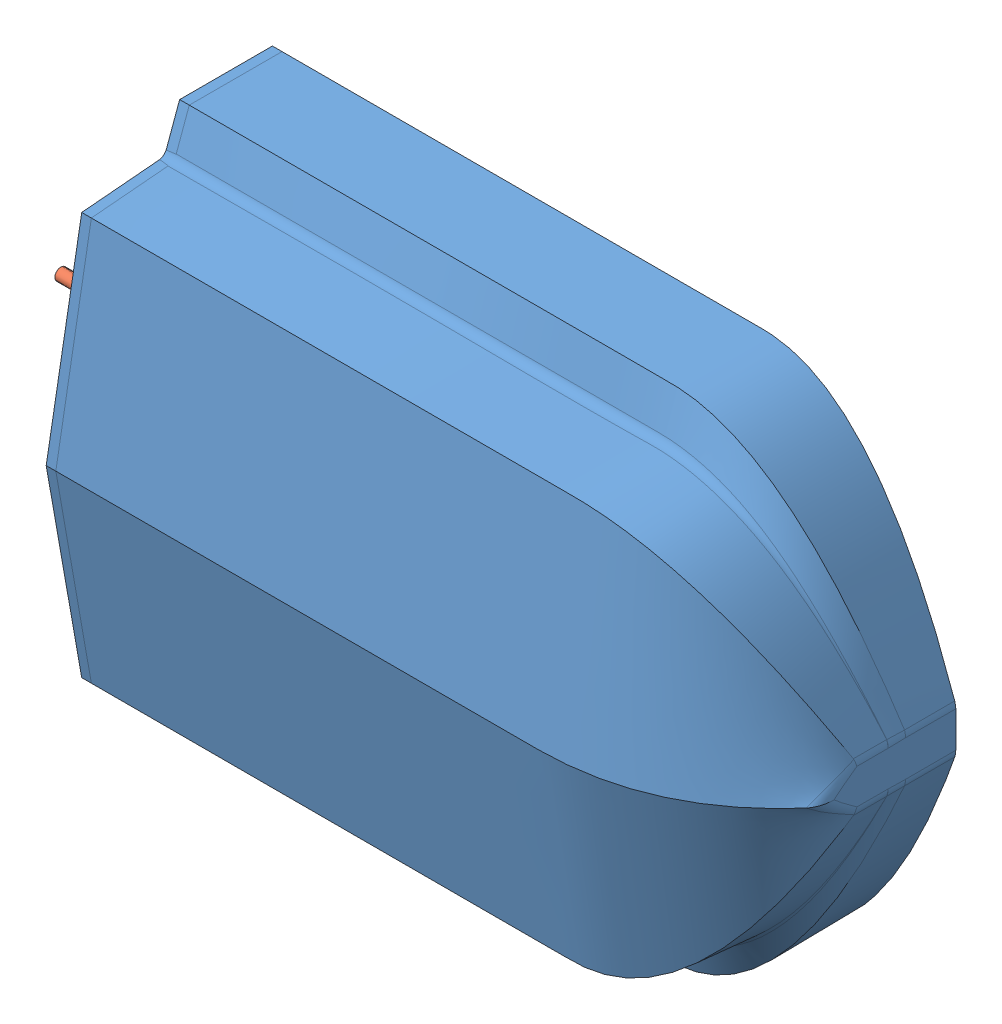
SolidWorks assembly Boat_Assem, configuration Default. Lengths in mm.
Overall size (99.88 66.55 32.05).
3 component instances, 2 part files, 3 mates.
Components (placement in the parent):
- hull_wide_no_mounts-1: hull_wide_no_mounts [Default] at origin size (92.02 66.55 32.05)
- Motor-1: Motor [Default] at (28.6004 4.4224 18.0675) x (0 0.984808 -0.173648) z (0 0.173648 0.984808) size (19.05 38.1 15.88)
- Motor-2: Motor [Default] at (28.6004 -23.1566 14.8192) x (0 0.985781 0.168034) z (0 -0.168034 0.985781) size (19.05 38.1 15.88)
Mates (geometry in assembly coordinates):
- Concentric1: concentric aligned: circle of hull_wide_no_mounts-1; circle of Motor-1
- Coincident2: coincident anti-aligned: plane of hull_wide_no_mounts-1 through (0.0254 0 0) normal (1 0 0); plane of Motor-2 through (0.0254 -23.1566 14.8192) normal (-1 0 0)
- Concentric2: concentric aligned: circle of hull_wide_no_mounts-1; circle of Motor-2
